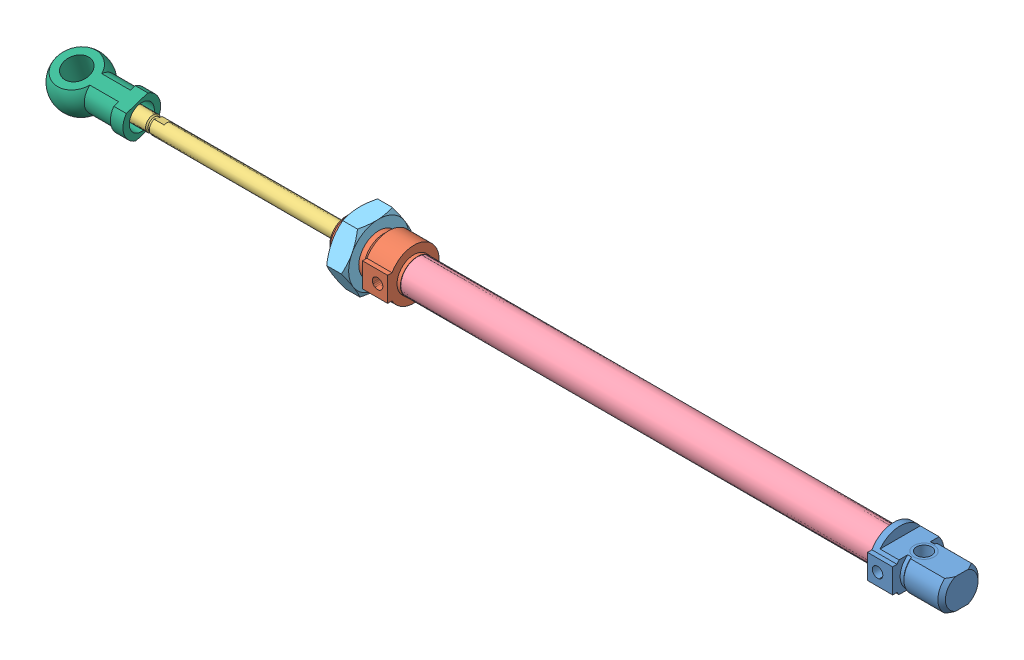
SolidWorks assembly Janatics-A51, A52 Series, configuration A51, A52 Series. Lengths in mm.
Overall size (360.34 36.26 35.11).
6 component instances, 6 part files, 19 mates.
Components (placement in the parent):
- Janatics-A51, A52 Series_REC-1(new)-1: Janatics-A51, A52 Series_REC-1(new) [DIA 12] x (-1 0 0) z (0 1 0) size (33 20.5 20)
- Janatics-A51, A52 Series_FEC(new)-1: Janatics-A51, A52 Series_FEC(new) [Default] at (-245 0 0) x (1 0 0) z (0 -1 0) size (33 20.5 20)
- Janatics-A51, A52 Series_piston rod (10C)(new)-1: Janatics-A51, A52 Series_piston rod (10C)(new) [DIA 12] at (-103.3403 0 0) x (-1 0 0) z (0 0.978558 -0.205972) size (233 12 12)
- Janatics-A51, A52 Series_cylinder barral (10A)(new)-1: Janatics-A51, A52 Series_cylinder barral (10A)(new) [Dia 12] at (554.2482 0.0003 -0.0003) x (1 0 0) z (0 0.695621 0.718409) size (188.3 13.3 13.3)
- Janatics-A51, A52 Series_lock nut Dia12-1: Janatics-A51, A52 Series_lock nut Dia12 [Dia 12] at (-240 0 0) x (1 0 0) z (0 0.84439 0.535729) size (8 24 27.71)
- rod eye-1: rod eye [Default] at (-331.3403 0 0) x (0 0.949155 0.31481) z (1 0 0) size (12 20 34)
Mates (geometry in assembly coordinates):
- Concentric1: concentric aligned: cylinder of Janatics-A51, A52 Series_REC-1(new)-1 through (-45.5 0 0) axis (-1 0 0) radius 6
- Coincident2: coincident aligned: plane of Janatics-A51, A52 Series_REC-1(new)-1 through (0 0 0) normal (1 0 0)
- Concentric2: concentric aligned: cylinder of Janatics-A51, A52 Series_cylinder barral (10A)(new)-1 through (-212 0 0) axis (-1 0 0) radius 6
- Concentric3: concentric anti-aligned: cylinder of Janatics-A51, A52 Series_piston rod (10C)(new)-1 through (-76.9491 0 0) axis (1 0 0) radius 6
- Coincident9: coincident aligned: plane of Janatics-A51, A52 Series_FEC(new)-1 through (-212 0 0) normal (1 0 0)
- Concentric4: concentric anti-aligned: cylinder of Janatics-A51, A52 Series_FEC(new)-1 through (-199.5 0 0) axis (1 0 0) radius 6
- Coincident12: coincident anti-aligned: plane of Janatics-A51, A52 Series_REC-1(new)-1 through (-28.35 0 6.75) normal (-1 0 0); plane of Janatics-A51, A52 Series_cylinder barral (10A)(new)-1 through (-28.35 -4.3105 4.1737) normal (1 0 0)
- Concentric5: concentric anti-aligned: cylinder of Janatics-A51, A52 Series_REC-1(new)-1 through (0 0 0) axis (1 0 0) radius 8; cylinder of Janatics-A51, A52 Series_lock nut Dia12-1 through (-240 0 0) axis (-1 0 0) radius 7.25
- Distance2: distance = 5 mm aligned: plane of Janatics-A51, A52 Series_FEC(new)-1 through (-245 0 0) normal (-1 0 0); plane of Janatics-A51, A52 Series_lock nut Dia12-1 through (-240 -11.7002 -7.4233) normal (-1 0 0)
- Concentric7: concentric anti-aligned: cylinder of Janatics-A51, A52 Series_piston rod (10C)(new)-1 through (-76.9491 0 0) axis (1 0 0) radius 3; cylinder of Janatics-A51, A52 Series_piston rod lock nut-1 through (-269 0 0) axis (-1 0 0) radius 2.5
- Distance3: distance = 3 mm aligned: plane of Janatics-A51, A52 Series_piston rod lock nut-1 through (-269 -0.2411 5.7685) normal (-1 0 0); plane of Janatics-A51, A52 Series_piston rod (10C)(new)-1 through (-336.3403 -0.6179 -2.9357) normal (-1 0 0)
- Coincident15: coincident aligned: plane of Janatics-A51, A52 Series_REC-1(new)-1 through (0 0 0) normal (0 0 1); plane of Janatics-A51, A52 Series_FEC(new)-1 through (-245 0 0) normal (0 0 1)
- Parallel3: parallel anti-aligned: plane of Janatics-A51, A52 Series_REC-1(new)-1 through (0 -6 8) normal (0 -1 0)
- Parallel9: parallel aligned: plane of Janatics-A51, A52 Series_lock nut Dia12-1 through (-232 -11.7002 -7.4233) normal (0 -0.463399 -0.88615); plane of Janatics-A51, A52 Series_piston rod lock nut-1 through (-266 -4.8751 -3.093) normal (0 -0.463399 -0.88615)
- Parallel10: parallel aligned: plane of Janatics-A51, A52 Series_piston rod (10C)(new)-1 through (-336.3403 -0.6179 -2.9357) normal (-1 0 0); plane of Janatics-A51, A52 Series_lock nut Dia12-1 through (-240 -11.7002 -7.4233) normal (-1 0 0)
- LimitDistance1: limit distance = 95.6597 mm anti-aligned: plane of Janatics-A51, A52 Series_piston rod (10C)(new)-1 through (-122.3403 -0.6179 -2.9357) normal (-1 0 0); plane of Janatics-A51, A52 Series_FEC(new)-1 through (-218 0 14) normal (1 0 0)
- Concentric8: concentric anti-aligned: cylinder of Janatics-A51, A52 Series_piston rod (10C)(new)-1 through (-76.9491 0 0) axis (1 0 0) radius 3; cylinder of rod eye-1 through (-326.3403 0 0) axis (-1 0 0) radius 5
- Coincident16: coincident anti-aligned: plane of Janatics-A51, A52 Series_piston rod (10C)(new)-1 through (-336.3403 -0.6179 -2.9357) normal (-1 0 0); plane of rod eye-1 through (-336.3403 0 0) normal (1 0 0)
- LimitDistance2: limit distance = 81.3403 mm anti-aligned: plane of rod eye-1 through (-326.3403 0 0) normal (1 0 0); plane of Janatics-A51, A52 Series_FEC(new)-1 through (-245 0 0) normal (-1 0 0)
